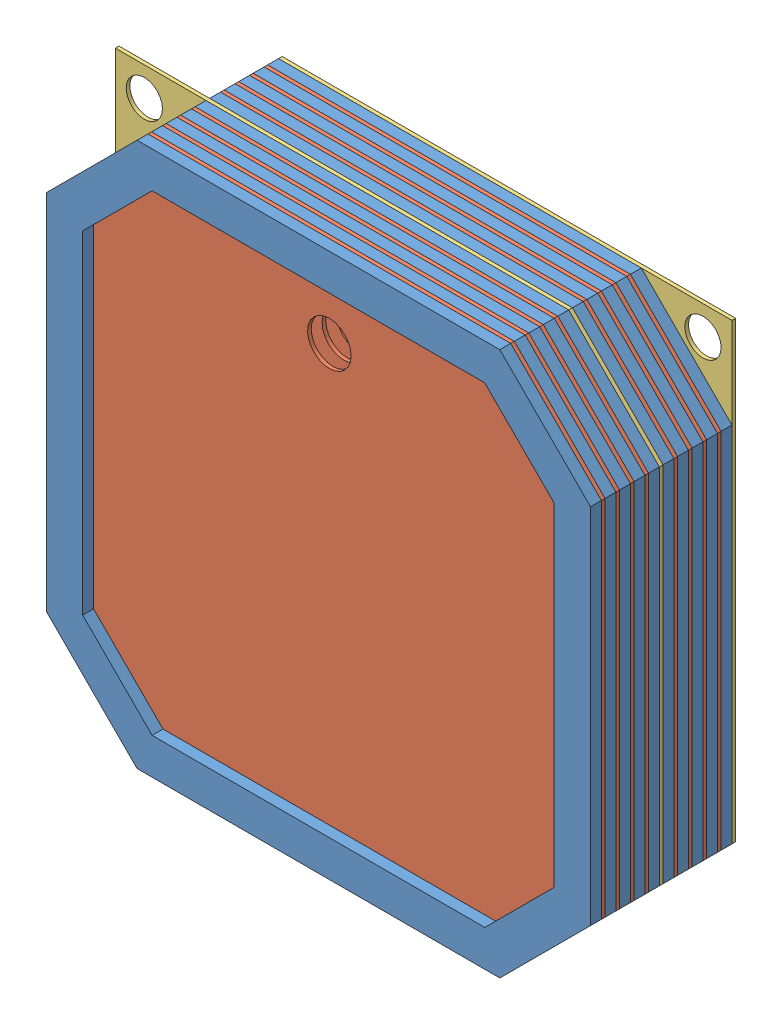
SolidWorks assembly Block Battery, configuration Default. Lengths in mm.
Overall size (150 150 40).
20 component instances, 3 part files, 36 mates.
Components (placement in the parent):
- Gasket-12: Gasket [Default] at (244.3004 275.7985 390.286) size (150 150 3)
- Plate-1-7: Plate-1 [Default] at (239.8004 279.4658 389.286) size (150 150 1)
- Gasket-13: Gasket [Default] at (244.3004 275.7985 386.286) size (150 150 3)
- Plate-1-8: Plate-1 [Default] at (239.8004 279.4658 385.286) size (150 150 1)
- Gasket-14: Gasket [Default] at (244.3004 275.7985 382.286) size (150 150 3)
- Plate-2-4: Plate-2 [Default] at (239.8004 279.4658 381.286) size (150 150 1)
- Plate-1-10: Plate-1 [Default] at (239.8004 279.4658 393.286) size (150 150 1)
- Gasket-16: Gasket [Default] at (244.3004 275.7985 394.286) size (150 150 3)
- Plate-1-11: Plate-1 [Default] at (239.8004 279.4658 397.286) size (150 150 1)
- Gasket-17: Gasket [Default] at (244.3004 275.7985 398.286) size (150 150 3)
- Plate-2-5: Plate-2 [Default] at (239.8004 279.4658 402.286) x (-1 0 0) z (0 0 -1) size (150 150 1)
- Gasket-18: Gasket [Default] at (244.3004 275.7985 402.286) size (150 150 3)
- Plate-1-12: Plate-1 [Default] at (239.8004 279.4658 405.286) size (150 150 1)
- Gasket-19: Gasket [Default] at (244.3004 275.7985 406.286) size (150 150 3)
- Plate-1-13: Plate-1 [Default] at (239.8004 279.4658 409.286) size (150 150 1)
- Gasket-20: Gasket [Default] at (244.3004 275.7985 410.286) size (150 150 3)
- Plate-1-14: Plate-1 [Default] at (239.8004 279.4658 413.286) size (150 150 1)
- Gasket-21: Gasket [Default] at (244.3004 275.7985 414.286) size (150 150 3)
- Plate-1-15: Plate-1 [Default] at (239.8004 279.4658 417.286) size (150 150 1)
- Gasket-22: Gasket [Default] at (244.3004 275.7985 418.286) size (150 150 3)
Mates (geometry in assembly coordinates):
- Coincident27: coincident: point of Gasket-12; point of Plate-1-7
- Coincident28: coincident: point of Plate-1-7; point of Gasket-13
- Coincident29: coincident: point of Gasket-13; point of Plate-1-8
- Coincident30: coincident: point of Plate-1-8; point of Gasket-14
- Coincident31: coincident: point of Gasket-14; point of Plate-2-4
- Concentric1: concentric: circle of Plate-1-7; circle of Plate-1-10
- Distance3: distance = 0 mm: plane of Plate-1-10 through (239.8004 279.4658 393.286) normal (0 0 -1); plane of Gasket-12 through (244.3004 275.7985 393.286) normal (0 0 1)
- Parallel1: parallel: line of Gasket-12 through (314.8004 229.4658 390.286) axis (0 1 0); line of Plate-1-10 through (314.8004 229.4658 394.286) axis (0 1 0)
- Parallel2: parallel: line of Plate-1-10 through (314.8004 229.4658 394.286) axis (0 1 0); line of Gasket-16 through (314.8004 229.4658 397.286) axis (0 1 0)
- Parallel3: parallel: plane of Plate-1-10 through (239.8004 279.4658 394.286) normal (0 0 1); plane of Gasket-16 through (244.3004 275.7985 394.286) normal (0 0 -1)
- Coincident37: coincident: point of Plate-1-10; point of Gasket-16
- Parallel4: parallel: line of Gasket-16 through (314.8004 229.4658 397.286) axis (0 1 0); line of Plate-1-11 through (314.8004 229.4658 398.286) axis (0 1 0)
- Parallel5: parallel: plane of Gasket-16 through (244.3004 275.7985 397.286) normal (0 0 1); plane of Plate-1-11 through (239.8004 279.4658 397.286) normal (0 0 -1)
- Coincident39: coincident: point of Gasket-16; point of Plate-1-11
- Parallel6: parallel: plane of Plate-1-11 through (239.8004 279.4658 398.286) normal (0 0 1); plane of Gasket-17 through (244.3004 275.7985 398.286) normal (0 0 -1)
- Coincident40: coincident: point of Plate-1-11; point of Gasket-17
- Parallel7: parallel: plane of Plate-1-11 through (239.8004 279.4658 398.286) normal (0 0 1); plane of Plate-2-5 through (239.8004 279.4658 402.286) normal (0 0 1)
- Coincident41: coincident: point of Gasket-17; point of Plate-2-5
- Parallel8: parallel: plane of Plate-2-5 through (239.8004 279.4658 402.286) normal (0 0 1); plane of Gasket-18 through (244.3004 275.7985 405.286) normal (0 0 1)
- Coincident42: coincident: point of Plate-2-5; point of Gasket-18
- Parallel9: parallel: plane of Plate-2-5 through (239.8004 279.4658 402.286) normal (0 0 1); plane of Plate-1-12 through (239.8004 279.4658 406.286) normal (0 0 1)
- Coincident43: coincident: point of Gasket-18; point of Plate-1-12
- Parallel10: parallel: plane of Plate-1-12 through (239.8004 279.4658 406.286) normal (0 0 1); plane of Gasket-19 through (244.3004 275.7985 409.286) normal (0 0 1)
- Coincident44: coincident: point of Plate-1-12; point of Gasket-19
- Parallel11: parallel: plane of Plate-1-12 through (239.8004 279.4658 406.286) normal (0 0 1); plane of Plate-1-13 through (239.8004 279.4658 410.286) normal (0 0 1)
- Coincident45: coincident: point of Gasket-19; point of Plate-1-13
- Parallel12: parallel: plane of Plate-1-13 through (239.8004 279.4658 410.286) normal (0 0 1); plane of Gasket-20 through (244.3004 275.7985 413.286) normal (0 0 1)
- Coincident46: coincident: point of Plate-1-13; point of Gasket-20
- Parallel13: parallel: plane of Plate-1-13 through (239.8004 279.4658 410.286) normal (0 0 1); plane of Plate-1-14 through (239.8004 279.4658 414.286) normal (0 0 1)
- Coincident47: coincident: point of Gasket-20; point of Plate-1-14
- Parallel14: parallel: plane of Plate-1-14 through (239.8004 279.4658 414.286) normal (0 0 1); plane of Gasket-21 through (244.3004 275.7985 417.286) normal (0 0 1)
- Coincident48: coincident: point of Plate-1-14; point of Gasket-21
- Parallel15: parallel: plane of Plate-1-14 through (239.8004 279.4658 414.286) normal (0 0 1); plane of Plate-1-15 through (239.8004 279.4658 418.286) normal (0 0 1)
- Coincident49: coincident: point of Gasket-21; point of Plate-1-15
- Parallel16: parallel: plane of Plate-1-15 through (239.8004 279.4658 418.286) normal (0 0 1); plane of Gasket-22 through (244.3004 275.7985 421.286) normal (0 0 1)
- Coincident50: coincident: point of Plate-1-15; point of Gasket-22
